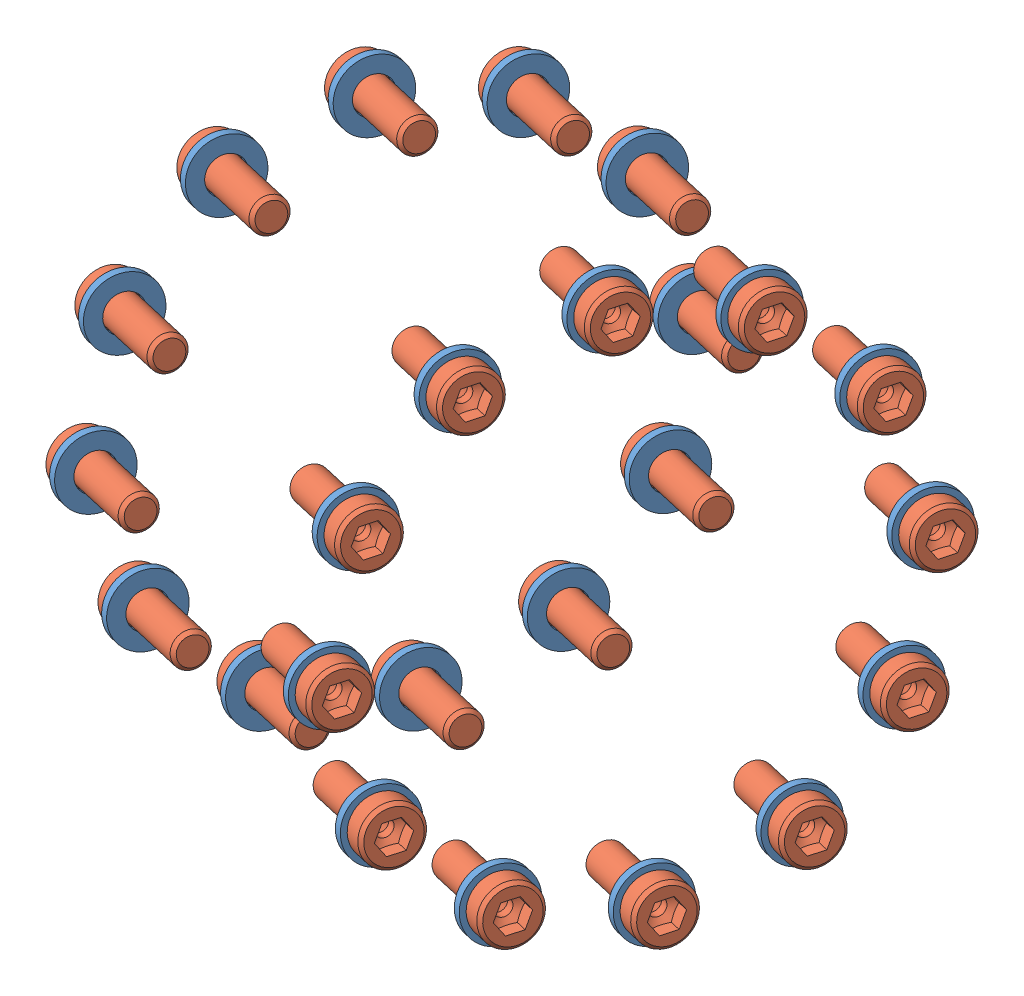
SolidWorks assembly PUTM-S-TR-DI-Drexler, configuration Domyślna. Lengths in mm.
Overall size (116.95 112.22 120.93).
48 component instances, 2 part files, 0 mates.
Components (placement in the parent):
- PUTM-S-TR-DI-DIN-125-A6.4-25: PUTM-S-TR-DI-DIN-125-A6.4 [Domyślna] at (-90.1252 -1060.6078 -324.0896) x (0.92443 0.168494 0.34211) z (-0.336565 -0.061345 0.93966) size (1.6 12 12)
- PUTM-S-TR-DI-DIN-125-A6.4-26: PUTM-S-TR-DI-DIN-125-A6.4 [Domyślna] at (-98.4581 -1103.9504 -280.2264) x (0.92443 0.168494 0.34211) z (-0.336565 -0.061345 0.93966) size (1.6 12 12)
- PUTM-S-TR-DI-DIN-125-A6.4-27: PUTM-S-TR-DI-DIN-125-A6.4 [Domyślna] at (-107.0261 -1098.1256 -259.9431) x (0.92443 0.168494 0.34211) z (-0.336565 -0.061345 0.93966) size (1.6 12 12)
- PUTM-S-TR-DI-DIN-125-A6.4-28: PUTM-S-TR-DI-DIN-125-A6.4 [Domyślna] at (-115.1587 -1082.2404 -245.7914) x (0.92443 0.168494 0.34211) z (-0.336565 -0.061345 0.93966) size (1.6 12 12)
- PUTM-S-TR-DI-DIN-125-A6.4-29: PUTM-S-TR-DI-DIN-125-A6.4 [Domyślna] at (-120.6767 -1060.5512 -241.5632) x (0.92443 0.168494 0.34211) z (-0.336565 -0.061345 0.93966) size (1.6 12 12)
- PUTM-S-TR-DI-DIN-125-A6.4-30: PUTM-S-TR-DI-DIN-125-A6.4 [Domyślna] at (-122.1016 -1038.8695 -248.3914) x (0.92443 0.168494 0.34211) z (-0.336565 -0.061345 0.93966) size (1.6 12 12)
- PUTM-S-TR-DI-DIN-125-A6.4-31: PUTM-S-TR-DI-DIN-125-A6.4 [Domyślna] at (-119.0515 -1023.005 -264.4465) x (0.92443 0.168494 0.34211) z (-0.336565 -0.061345 0.93966) size (1.6 12 12)
- PUTM-S-TR-DI-DIN-125-A6.4-32: PUTM-S-TR-DI-DIN-125-A6.4 [Domyślna] at (-112.3439 -1017.2085 -285.4264) x (0.92443 0.168494 0.34211) z (-0.336565 -0.061345 0.93966) size (1.6 12 12)
- PUTM-S-TR-DI-DIN-125-A6.4-33: PUTM-S-TR-DI-DIN-125-A6.4 [Domyślna] at (-103.7758 -1023.0333 -305.7097) x (0.92443 0.168494 0.34211) z (-0.336565 -0.061345 0.93966) size (1.6 12 12)
- PUTM-S-TR-DI-DIN-125-A6.4-34: PUTM-S-TR-DI-DIN-125-A6.4 [Domyślna] at (-95.6432 -1038.9185 -319.8614) x (0.92443 0.168494 0.34211) z (-0.336565 -0.061345 0.93966) size (1.6 12 12)
- PUTM-S-TR-DI-DIN-125-A6.4-35: PUTM-S-TR-DI-DIN-125-A6.4 [Domyślna] at (-88.7003 -1082.2894 -317.2614) x (0.92443 0.168494 0.34211) z (-0.336565 -0.061345 0.93966) size (1.6 12 12)
- PUTM-S-TR-DI-DIN-125-A6.4-36: PUTM-S-TR-DI-DIN-125-A6.4 [Domyślna] at (-91.7504 -1098.1539 -301.2063) x (0.92443 0.168494 0.34211) z (-0.336565 -0.061345 0.93966) size (1.6 12 12)
- PUTM-S-TR-DI-DIN-125-A6.4-37: PUTM-S-TR-DI-DIN-125-A6.4 [Domyślna] at (-163.6813 -1051.3196 -345.0407) x (-0.92443 -0.168494 -0.34211) z (-0.336565 -0.061345 0.93966) size (1.6 12 12)
- PUTM-S-TR-DI-DIN-125-A6.4-38: PUTM-S-TR-DI-DIN-125-A6.4 [Domyślna] at (-166.4961 -1116.3515 -305.4057) x (-0.92443 -0.168494 -0.34211) z (-0.336565 -0.061345 0.93966) size (1.6 12 12)
- PUTM-S-TR-DI-DIN-125-A6.4-39: PUTM-S-TR-DI-DIN-125-A6.4 [Domyślna] at (-175.0641 -1110.5268 -285.1224) x (-0.92443 -0.168494 -0.34211) z (-0.336565 -0.061345 0.93966) size (1.6 12 12)
- PUTM-S-TR-DI-DIN-125-A6.4-40: PUTM-S-TR-DI-DIN-125-A6.4 [Domyślna] at (-183.1967 -1094.6415 -270.9707) x (-0.92443 -0.168494 -0.34211) z (-0.336565 -0.061345 0.93966) size (1.6 12 12)
- PUTM-S-TR-DI-DIN-125-A6.4-41: PUTM-S-TR-DI-DIN-125-A6.4 [Domyślna] at (-188.7147 -1072.9523 -266.7425) x (-0.92443 -0.168494 -0.34211) z (-0.336565 -0.061345 0.93966) size (1.6 12 12)
- PUTM-S-TR-DI-DIN-125-A6.4-42: PUTM-S-TR-DI-DIN-125-A6.4 [Domyślna] at (-190.1396 -1051.2706 -273.5707) x (-0.92443 -0.168494 -0.34211) z (-0.336565 -0.061345 0.93966) size (1.6 12 12)
- PUTM-S-TR-DI-DIN-125-A6.4-43: PUTM-S-TR-DI-DIN-125-A6.4 [Domyślna] at (-187.0896 -1035.4061 -289.6258) x (-0.92443 -0.168494 -0.34211) z (-0.336565 -0.061345 0.93966) size (1.6 12 12)
- PUTM-S-TR-DI-DIN-125-A6.4-44: PUTM-S-TR-DI-DIN-125-A6.4 [Domyślna] at (-180.3819 -1029.6097 -310.6057) x (-0.92443 -0.168494 -0.34211) z (-0.336565 -0.061345 0.93966) size (1.6 12 12)
- PUTM-S-TR-DI-DIN-125-A6.4-45: PUTM-S-TR-DI-DIN-125-A6.4 [Domyślna] at (-171.8139 -1035.4344 -330.889) x (-0.92443 -0.168494 -0.34211) z (-0.336565 -0.061345 0.93966) size (1.6 12 12)
- PUTM-S-TR-DI-DIN-125-A6.4-46: PUTM-S-TR-DI-DIN-125-A6.4 [Domyślna] at (-158.1633 -1073.0089 -349.2689) x (-0.92443 -0.168494 -0.34211) z (-0.336565 -0.061345 0.93966) size (1.6 12 12)
- PUTM-S-TR-DI-DIN-125-A6.4-47: PUTM-S-TR-DI-DIN-125-A6.4 [Domyślna] at (-156.7384 -1094.6906 -342.4407) x (-0.92443 -0.168494 -0.34211) z (-0.336565 -0.061345 0.93966) size (1.6 12 12)
- PUTM-S-TR-DI-DIN-125-A6.4-48: PUTM-S-TR-DI-DIN-125-A6.4 [Domyślna] at (-159.7884 -1110.5551 -326.3856) x (-0.92443 -0.168494 -0.34211) z (-0.336565 -0.061345 0.93966) size (1.6 12 12)
- PUTM-S-TR-DI-DIN-6912-M6x16-1: PUTM-S-TR-DI-DIN-6912-M6x16 [Domyślna] at (-165.1604 -1051.5892 -345.5881) x (0.92443 0.168494 0.34211) z (-0.336565 -0.061345 0.93966) size (20 10 10)
- PUTM-S-TR-DI-DIN-6912-M6x16-2: PUTM-S-TR-DI-DIN-6912-M6x16 [Domyślna] at (-159.6424 -1073.2785 -349.8163) x (0.92443 0.168494 0.34211) z (-0.336565 -0.061345 0.93966) size (20 10 10)
- PUTM-S-TR-DI-DIN-6912-M6x16-3: PUTM-S-TR-DI-DIN-6912-M6x16 [Domyślna] at (-158.2175 -1094.9601 -342.9881) x (0.92443 0.168494 0.34211) z (-0.336565 -0.061345 0.93966) size (20 10 10)
- PUTM-S-TR-DI-DIN-6912-M6x16-4: PUTM-S-TR-DI-DIN-6912-M6x16 [Domyślna] at (-161.2675 -1110.8246 -326.933) x (0.92443 0.168494 0.34211) z (-0.336565 -0.061345 0.93966) size (20 10 10)
- PUTM-S-TR-DI-DIN-6912-M6x16-5: PUTM-S-TR-DI-DIN-6912-M6x16 [Domyślna] at (-167.9752 -1116.6211 -305.9531) x (0.92443 0.168494 0.34211) z (-0.336565 -0.061345 0.93966) size (20 10 10)
- PUTM-S-TR-DI-DIN-6912-M6x16-6: PUTM-S-TR-DI-DIN-6912-M6x16 [Domyślna] at (-176.5432 -1110.7963 -285.6698) x (0.92443 0.168494 0.34211) z (-0.336565 -0.061345 0.93966) size (20 10 10)
- PUTM-S-TR-DI-DIN-6912-M6x16-7: PUTM-S-TR-DI-DIN-6912-M6x16 [Domyślna] at (-184.6758 -1094.9111 -271.5181) x (0.92443 0.168494 0.34211) z (-0.336565 -0.061345 0.93966) size (20 10 10)
- PUTM-S-TR-DI-DIN-6912-M6x16-8: PUTM-S-TR-DI-DIN-6912-M6x16 [Domyślna] at (-190.1938 -1073.2219 -267.2899) x (0.92443 0.168494 0.34211) z (-0.336565 -0.061345 0.93966) size (20 10 10)
- PUTM-S-TR-DI-DIN-6912-M6x16-9: PUTM-S-TR-DI-DIN-6912-M6x16 [Domyślna] at (-191.6187 -1051.5402 -274.1181) x (0.92443 0.168494 0.34211) z (-0.336565 -0.061345 0.93966) size (20 10 10)
- PUTM-S-TR-DI-DIN-6912-M6x16-10: PUTM-S-TR-DI-DIN-6912-M6x16 [Domyślna] at (-188.5687 -1035.6757 -290.1732) x (0.92443 0.168494 0.34211) z (-0.336565 -0.061345 0.93966) size (20 10 10)
- PUTM-S-TR-DI-DIN-6912-M6x16-11: PUTM-S-TR-DI-DIN-6912-M6x16 [Domyślna] at (-181.861 -1029.8793 -311.1531) x (0.92443 0.168494 0.34211) z (-0.336565 -0.061345 0.93966) size (20 10 10)
- PUTM-S-TR-DI-DIN-6912-M6x16-12: PUTM-S-TR-DI-DIN-6912-M6x16 [Domyślna] at (-173.293 -1035.704 -331.4364) x (0.92443 0.168494 0.34211) z (-0.336565 -0.061345 0.93966) size (20 10 10)
- PUTM-S-TR-DI-DIN-6912-M6x16-13: PUTM-S-TR-DI-DIN-6912-M6x16 [Domyślna] at (-120.6225 -1038.5999 -247.8441) x (-0.92443 -0.168494 -0.34211) z (-0.336565 -0.061345 0.93966) size (20 10 10)
- PUTM-S-TR-DI-DIN-6912-M6x16-14: PUTM-S-TR-DI-DIN-6912-M6x16 [Domyślna] at (-119.1976 -1060.2816 -241.0158) x (-0.92443 -0.168494 -0.34211) z (-0.336565 -0.061345 0.93966) size (20 10 10)
- PUTM-S-TR-DI-DIN-6912-M6x16-15: PUTM-S-TR-DI-DIN-6912-M6x16 [Domyślna] at (-113.6796 -1081.9708 -245.244) x (-0.92443 -0.168494 -0.34211) z (-0.336565 -0.061345 0.93966) size (20 10 10)
- PUTM-S-TR-DI-DIN-6912-M6x16-16: PUTM-S-TR-DI-DIN-6912-M6x16 [Domyślna] at (-105.547 -1097.856 -259.3957) x (-0.92443 -0.168494 -0.34211) z (-0.336565 -0.061345 0.93966) size (20 10 10)
- PUTM-S-TR-DI-DIN-6912-M6x16-17: PUTM-S-TR-DI-DIN-6912-M6x16 [Domyślna] at (-96.979 -1103.6808 -279.679) x (-0.92443 -0.168494 -0.34211) z (-0.336565 -0.061345 0.93966) size (20 10 10)
- PUTM-S-TR-DI-DIN-6912-M6x16-18: PUTM-S-TR-DI-DIN-6912-M6x16 [Domyślna] at (-90.2713 -1097.8843 -300.6589) x (-0.92443 -0.168494 -0.34211) z (-0.336565 -0.061345 0.93966) size (20 10 10)
- PUTM-S-TR-DI-DIN-6912-M6x16-19: PUTM-S-TR-DI-DIN-6912-M6x16 [Domyślna] at (-87.2213 -1082.0198 -316.714) x (-0.92443 -0.168494 -0.34211) z (-0.336565 -0.061345 0.93966) size (20 10 10)
- PUTM-S-TR-DI-DIN-6912-M6x16-20: PUTM-S-TR-DI-DIN-6912-M6x16 [Domyślna] at (-88.6461 -1060.3382 -323.5422) x (-0.92443 -0.168494 -0.34211) z (-0.336565 -0.061345 0.93966) size (20 10 10)
- PUTM-S-TR-DI-DIN-6912-M6x16-21: PUTM-S-TR-DI-DIN-6912-M6x16 [Domyślna] at (-94.1642 -1038.6489 -319.314) x (-0.92443 -0.168494 -0.34211) z (-0.336565 -0.061345 0.93966) size (20 10 10)
- PUTM-S-TR-DI-DIN-6912-M6x16-22: PUTM-S-TR-DI-DIN-6912-M6x16 [Domyślna] at (-102.2967 -1022.7637 -305.1623) x (-0.92443 -0.168494 -0.34211) z (-0.336565 -0.061345 0.93966) size (20 10 10)
- PUTM-S-TR-DI-DIN-6912-M6x16-23: PUTM-S-TR-DI-DIN-6912-M6x16 [Domyślna] at (-110.8648 -1016.939 -284.8791) x (-0.92443 -0.168494 -0.34211) z (-0.336565 -0.061345 0.93966) size (20 10 10)
- PUTM-S-TR-DI-DIN-6912-M6x16-24: PUTM-S-TR-DI-DIN-6912-M6x16 [Domyślna] at (-117.5725 -1022.7354 -263.8991) x (-0.92443 -0.168494 -0.34211) z (-0.336565 -0.061345 0.93966) size (20 10 10)
